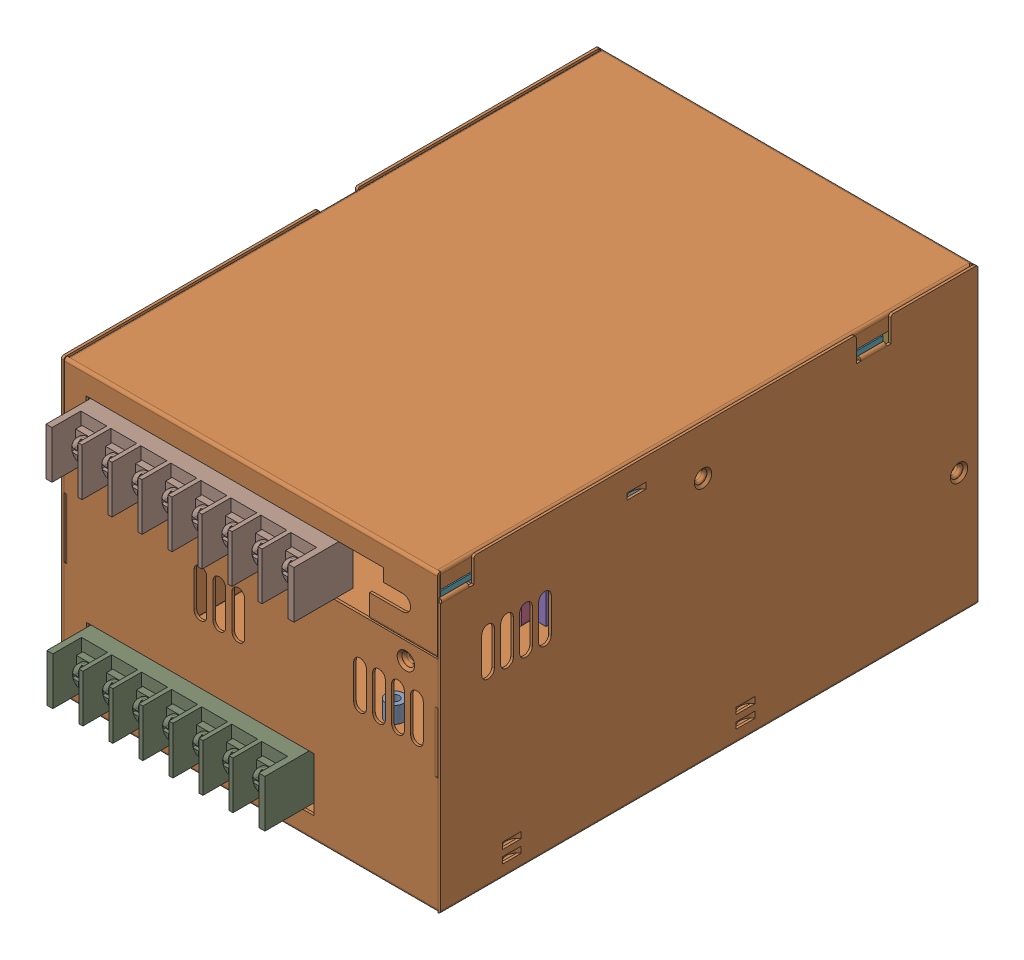
SolidWorks assembly PSPA-1000_ASM_38.ASM, configuration Default. Lengths in mm.
Overall size (120 93 184.15).
18 component instances, 11 part files, 0 mates.
Components (placement in the parent):
- CASE-D_ASM_2.ASM-1: CASE-D_ASM_2.ASM [Default] at origin size (120 93 170)
  - CUBONE_2.PRT-1: CUBONE_2.PRT [Default] at (59.5 0.5 -46) x (-1 0 0) z (0 0 1) size (7.5 6 6.5)
  - PSPA-10000-CASE-D_29.PRT-1: PSPA-10000-CASE-D_29.PRT [Default] at origin size (120 93 170)
- 1DL5-PQ3230-12P-VT_1.PRT-1: 1DL5-PQ3230-12P-VT_1.PRT [Default] at (57.1 59.1 -73) x (-1 0 0) z (0 -1 0) size (33.01 34.4 37.8)
- DT-4C-B14W-P8_5.PRT-1: DT-4C-B14W-P8_5.PRT [Default] at (9.2629 78.5 -4.5) x (1 0 0.000696) z (0 -1 0) size (78.5 18.6 15)
- DT-4C-B14W-P7_4.PRT-1: DT-4C-B14W-P7_4.PRT [Default] at (9 16.1 -5) x (1 0 0) z (0 -1 0) size (69 18.6 15)
- PSPA-1000-CU2_9.PRT-1: PSPA-1000-CU2_9.PRT [Default] at (87 87.6 -25.75) x (-1 0 0) z (0 1 0) size (46.75 7 4.1)
- PSPA-1000-CU1_38.PRT-1: PSPA-1000-CU1_38.PRT [Default] at (48.8006 59.5012 -44.5625) x (-1 0 0) z (0 0 1) size (4 37.25 8.5)
- PSPA-1000-CU1_38.PRT-2: PSPA-1000-CU1_38.PRT [Default] at (61.3006 59.5012 -44.5625) x (-1 0 0) z (0 0 1) size (4 37.25 8.5)
- PSPA-1000-CU1_38.PRT-3: PSPA-1000-CU1_38.PRT [Default] at (73.8006 59.5012 -44.5625) x (-1 0 0) z (0 0 1) size (4 37.25 8.5)
- PSPA-1000-CU1_38.PRT-4: PSPA-1000-CU1_38.PRT [Default] at (81.5506 59.5012 -44.5625) x (-1 0 0) z (0 0 1) size (4 37.25 8.5)
- PSPA-1000-CU1_38.PRT-5: PSPA-1000-CU1_38.PRT [Default] at (94.0506 59.5012 -44.5625) x (-1 0 0) z (0 0 1) size (4 37.25 8.5)
- PSPA-1000-CU1_38.PRT-6: PSPA-1000-CU1_38.PRT [Default] at (106.5506 59.5012 -44.5625) x (-1 0 0) z (0 0 1) size (4 37.25 8.5)
- PSPA-1000-PCBC_10.PRT-1: PSPA-1000-PCBC_10.PRT [Default] at (108.75 86 -44.5625) x (0 -1 0) z (0 0 1) size (35 73.5 1.6)
- FAN80-1_2.PRT-1: FAN80-1_2.PRT [Default] at (61.75 48.25 -156.7) x (1 0 0) z (0 1 0) size (80 25 80)
- PSPA-1000-PCBB_18.PRT-1: PSPA-1000-PCBB_18.PRT [Default] at (5 86 -87) x (0 0 -1) z (0 -1 0) size (140 118 1.6)
- 1HH267X15X5_2.PRT-1: 1HH267X15X5_2.PRT [Default] at (109.7 86.95 -39.8) x (0 0 -1) z (0 1 0) size (15 67 5)
- 1DL5-PQ3230-12P-VT_1.PRT-2: 1DL5-PQ3230-12P-VT_1.PRT [Default] at (93.1 59.1 -73) x (-1 0 0) z (0 -1 0) size (33.01 34.4 37.8)
